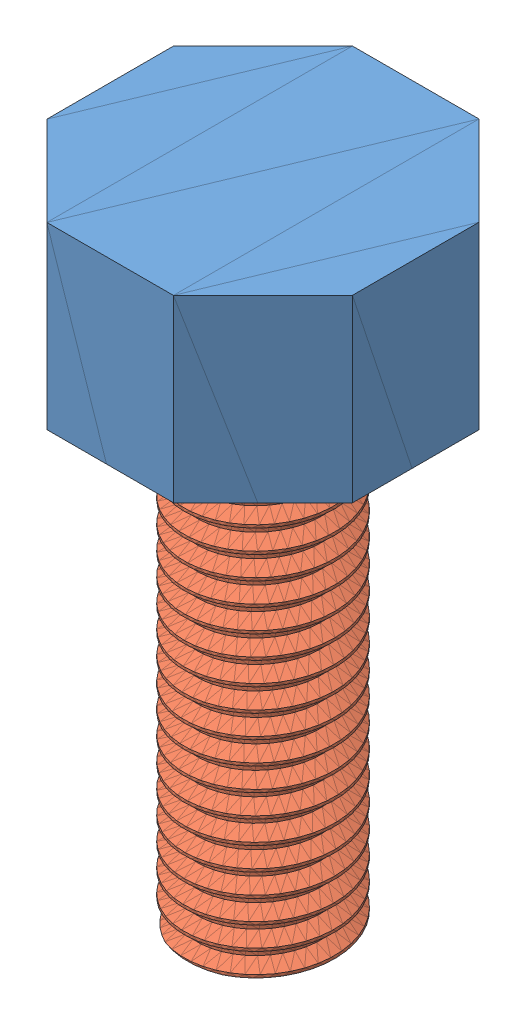
SolidWorks assembly screw3, configuration 默认. Lengths in mm.
Overall size (20.01 42.38 20).
2 component instances, 2 part files, 1 mates.
Components (placement in the parent):
- Screw2-1: Screw2 [默认] at (-10.0544 -69.3229 20.0093) size (20.01 11.76 20)
- Screw1-1: Screw1 [默认] at (-9.365 -16.6744 16.2307) x (0.925895 -0.000789 0.377779) z (-0.377779 0.000003 0.925896) size (9.87 30.84 9.85)
Mates (geometry in assembly coordinates):
- 同心1: concentric aligned: circle of Screw2-1; circle of Screw1-1
